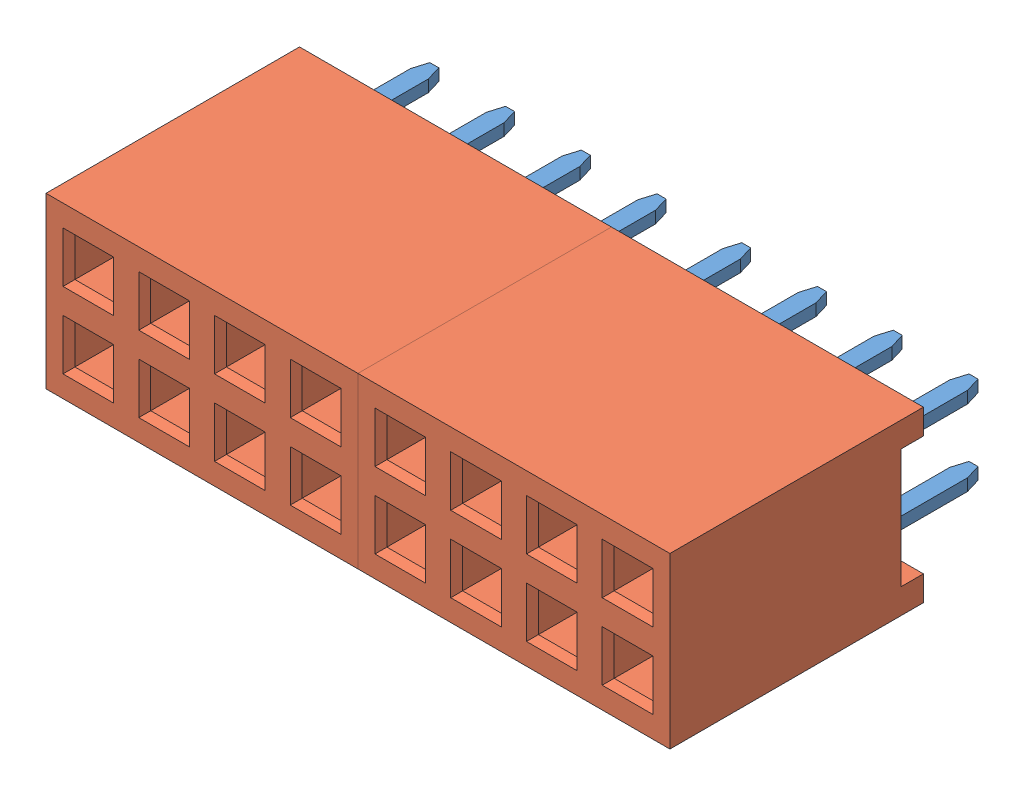
SolidWorks assembly HE10-16Way-Female, configuration Défaut. Lengths in mm.
Overall size (20.92 5.68 11.6).
20 component instances, 2 part files, 3 mates.
Components (placement in the parent):
- User Library-MULTICOMP 2214S-08SG-85-1: User Library-MULTICOMP 2214S-08SG-85 [Default] at (-3.5782 -0.0598 8.9002) size (10.46 5.68 11.6)
  - User Library-MULTICOMP 2214S-08SG-85_contact-1: User Library-MULTICOMP 2214S-08SG-85_contact [Default] at (-3.81 -1.07 0.9) x (1 0 0) z (0 -1 0) size (2 10 0.4)
  - User Library-MULTICOMP 2214S-08SG-85_contact-2: User Library-MULTICOMP 2214S-08SG-85_contact [Default] at (-3.81 1.47 0.9) x (1 0 0) z (0 -1 0) size (2 10 0.4)
  - User Library-MULTICOMP 2214S-08SG-85_contact-3: User Library-MULTICOMP 2214S-08SG-85_contact [Default] at (-1.27 -1.07 0.9) x (1 0 0) z (0 -1 0) size (2 10 0.4)
  - User Library-MULTICOMP 2214S-08SG-85_contact-4: User Library-MULTICOMP 2214S-08SG-85_contact [Default] at (-1.27 1.47 0.9) x (1 0 0) z (0 -1 0) size (2 10 0.4)
  - User Library-MULTICOMP 2214S-08SG-85_contact-5: User Library-MULTICOMP 2214S-08SG-85_contact [Default] at (1.27 1.47 0.9) x (1 0 0) z (0 -1 0) size (2 10 0.4)
  - User Library-MULTICOMP 2214S-08SG-85_contact-6: User Library-MULTICOMP 2214S-08SG-85_contact [Default] at (1.27 -1.07 0.9) x (1 0 0) z (0 -1 0) size (2 10 0.4)
  - User Library-MULTICOMP 2214S-08SG-85_contact-7: User Library-MULTICOMP 2214S-08SG-85_contact [Default] at (3.81 -1.47 0.9) x (-1 0 0) z (0 1 0) size (2 10 0.4)
  - User Library-MULTICOMP 2214S-08SG-85_contact-8: User Library-MULTICOMP 2214S-08SG-85_contact [Default] at (3.81 1.07 0.9) x (-1 0 0) z (0 1 0) size (2 10 0.4)
  - User Library-MULTICOMP 2214S-08SG-85_housing-1: User Library-MULTICOMP 2214S-08SG-85_housing [Default] at origin size (10.46 5.68 8.5)
- User Library-MULTICOMP 2214S-08SG-85-2: User Library-MULTICOMP 2214S-08SG-85 [Default] at (6.8818 -0.0598 8.9002) size (10.46 5.68 11.6)
  - User Library-MULTICOMP 2214S-08SG-85_contact-1: User Library-MULTICOMP 2214S-08SG-85_contact [Default] at (-3.81 -1.07 0.9) x (1 0 0) z (0 -1 0) size (2 10 0.4)
  - User Library-MULTICOMP 2214S-08SG-85_contact-2: User Library-MULTICOMP 2214S-08SG-85_contact [Default] at (-3.81 1.47 0.9) x (1 0 0) z (0 -1 0) size (2 10 0.4)
  - User Library-MULTICOMP 2214S-08SG-85_contact-3: User Library-MULTICOMP 2214S-08SG-85_contact [Default] at (-1.27 -1.07 0.9) x (1 0 0) z (0 -1 0) size (2 10 0.4)
  - User Library-MULTICOMP 2214S-08SG-85_contact-4: User Library-MULTICOMP 2214S-08SG-85_contact [Default] at (-1.27 1.47 0.9) x (1 0 0) z (0 -1 0) size (2 10 0.4)
  - User Library-MULTICOMP 2214S-08SG-85_contact-5: User Library-MULTICOMP 2214S-08SG-85_contact [Default] at (1.27 1.47 0.9) x (1 0 0) z (0 -1 0) size (2 10 0.4)
  - User Library-MULTICOMP 2214S-08SG-85_contact-6: User Library-MULTICOMP 2214S-08SG-85_contact [Default] at (1.27 -1.07 0.9) x (1 0 0) z (0 -1 0) size (2 10 0.4)
  - User Library-MULTICOMP 2214S-08SG-85_contact-7: User Library-MULTICOMP 2214S-08SG-85_contact [Default] at (3.81 -1.47 0.9) x (-1 0 0) z (0 1 0) size (2 10 0.4)
  - User Library-MULTICOMP 2214S-08SG-85_contact-8: User Library-MULTICOMP 2214S-08SG-85_contact [Default] at (3.81 1.07 0.9) x (-1 0 0) z (0 1 0) size (2 10 0.4)
  - User Library-MULTICOMP 2214S-08SG-85_housing-1: User Library-MULTICOMP 2214S-08SG-85_housing [Default] at origin size (10.46 5.68 8.5)
Mates (geometry in assembly coordinates):
- Coïncidente1: coincident: plane of User Library-MULTICOMP 2214S-08SG-85-1/User Library-MULTICOMP 2214S-08SG-85_housing-1 through (-3.5782 -0.0598 17.4002) normal (0 0 1); plane of User Library-MULTICOMP 2214S-08SG-85-2/User Library-MULTICOMP 2214S-08SG-85_housing-1 through (6.8818 -0.6282 17.4002) normal (0 0 1)
- Coïncidente2: coincident: plane of User Library-MULTICOMP 2214S-08SG-85-1/User Library-MULTICOMP 2214S-08SG-85_housing-1 through (1.6518 -2.8998 8.9002) normal (1 0 0); plane of User Library-MULTICOMP 2214S-08SG-85-2/User Library-MULTICOMP 2214S-08SG-85_housing-1 through (1.6518 2.2118 8.9002) normal (-1 0 0)
- Coïncidente3: coincident aligned: plane of User Library-MULTICOMP 2214S-08SG-85-1/User Library-MULTICOMP 2214S-08SG-85_housing-1 through (-3.5782 2.7802 8.9002) normal (0 1 0); plane of User Library-MULTICOMP 2214S-08SG-85-2/User Library-MULTICOMP 2214S-08SG-85_housing-1 through (6.8818 2.7802 8.9002) normal (0 1 0)
